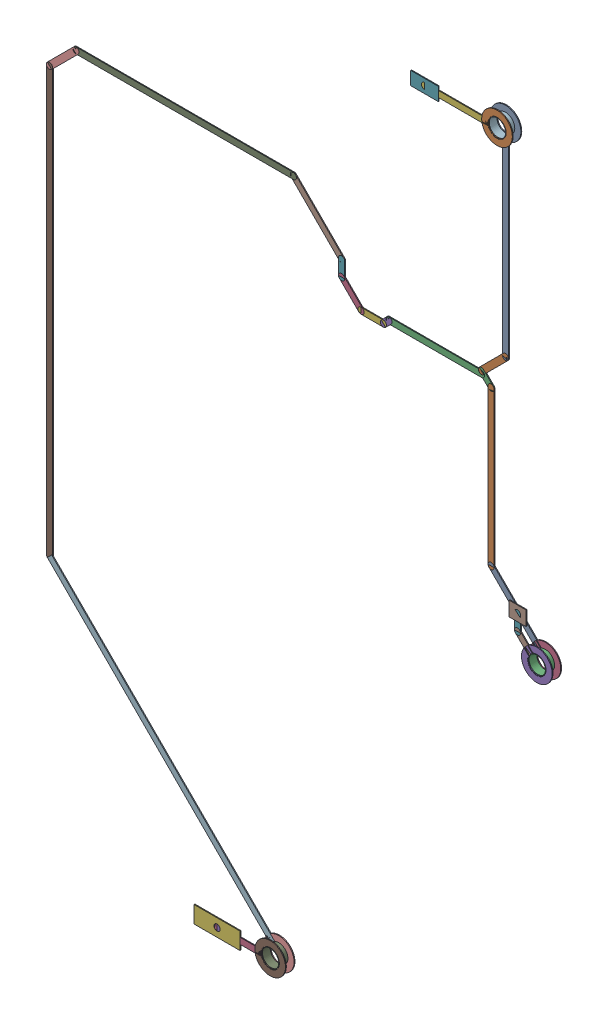
SolidWorks assembly SCL, configuration Predeterminado. Lengths in mm.
Overall size (21.31 35.77 0.39).
90 component instances, 25 part files, 0 mates.
Components (placement in the parent):
- Track (26.1mm,48.6mm)(26.1mm,57mm) on Bottom Layer-1: Track (26.1mm,48.6mm)(26.1mm,57mm) on Bottom Layer [Predeterminado] at origin size (0.25 8.2 0.04)
  - Track (26.1mm,48.6mm)(26.1mm,57mm) on Bottom Layer-1-1: Track (26.1mm,48.6mm)(26.1mm,57mm) on Bottom Layer-1 [Predeterminado] at (-68.317 -44.187 -0.4013) size (0.25 8.2 0.04)
    - Track (26.1mm,48.6mm)(26.1mm,57mm) on Bottom Layer-Part-1-1: Track (26.1mm,48.6mm)(26.1mm,57mm) on Bottom Layer-Part-1 [Predeterminado] at origin size (0.25 8.2 0.04)
- Track (25.1mm,47.6mm)(26.1mm,48.6mm) on Bottom Layer-1: Track (25.1mm,47.6mm)(26.1mm,48.6mm) on Bottom Layer [Predeterminado] at origin size (1.25 1.25 0.04)
  - Track (25.1mm,47.6mm)(26.1mm,48.6mm) on Bottom Layer-1-1: Track (25.1mm,47.6mm)(26.1mm,48.6mm) on Bottom Layer-1 [Predeterminado] at (-68.317 -44.187 -0.4013) size (1.25 1.25 0.04)
    - Track (25.1mm,47.6mm)(26.1mm,48.6mm) on Bottom Layer-Part-1-1: Track (25.1mm,47.6mm)(26.1mm,48.6mm) on Bottom Layer-Part-1 [Predeterminado] at origin size (1.25 1.25 0.04)
- Track (21.267mm,47.493mm)(25.1mm,47.493mm) on Bottom Layer-1: Track (21.267mm,47.493mm)(25.1mm,47.493mm) on Bottom Layer [Predeterminado] at origin size (4.09 0.25 0.04)
  - Track (21.267mm,47.493mm)(25.1mm,47.493mm) on Bottom Layer-1-1: Track (21.267mm,47.493mm)(25.1mm,47.493mm) on Bottom Layer-1 [Predeterminado] at (-68.317 -44.187 -0.4013) size (4.09 0.25 0.04)
    - Track (21.267mm,47.493mm)(25.1mm,47.493mm) on Bottom Layer-Part-1-1: Track (21.267mm,47.493mm)(25.1mm,47.493mm) on Bottom Layer-Part-1 [Predeterminado] at origin size (4.09 0.25 0.04)
- Track (19.304mm,48.07mm)(20.109mm,47.265mm) on Bottom Layer-1: Track (19.304mm,48.07mm)(20.109mm,47.265mm) on Bottom Layer [Predeterminado] at origin size (1.06 1.06 0.04)
  - Track (19.304mm,48.07mm)(20.109mm,47.265mm) on Bottom Layer-1-1: Track (19.304mm,48.07mm)(20.109mm,47.265mm) on Bottom Layer-1 [Predeterminado] at (-68.317 -44.187 -0.4013) size (1.06 1.06 0.04)
    - Track (19.304mm,48.07mm)(20.109mm,47.265mm) on Bottom Layer-Part-1-1: Track (19.304mm,48.07mm)(20.109mm,47.265mm) on Bottom Layer-Part-1 [Predeterminado] at origin size (1.06 1.06 0.04)
- Track (21.039mm,47.265mm)(21.267mm,47.493mm) on Bottom Layer-1: Track (21.039mm,47.265mm)(21.267mm,47.493mm) on Bottom Layer [Predeterminado] at origin size (0.48 0.48 0.04)
  - Track (21.039mm,47.265mm)(21.267mm,47.493mm) on Bottom Layer-1-1: Track (21.039mm,47.265mm)(21.267mm,47.493mm) on Bottom Layer-1 [Predeterminado] at (-68.317 -44.187 -0.4013) size (0.48 0.48 0.04)
    - Track (21.039mm,47.265mm)(21.267mm,47.493mm) on Bottom Layer-Part-1-1: Track (21.039mm,47.265mm)(21.267mm,47.493mm) on Bottom Layer-Part-1 [Predeterminado] at origin size (0.48 0.48 0.04)
- Track (20.109mm,47.265mm)(21.039mm,47.265mm) on Bottom Layer-1: Track (20.109mm,47.265mm)(21.039mm,47.265mm) on Bottom Layer [Predeterminado] at origin size (1.18 0.25 0.04)
  - Track (20.109mm,47.265mm)(21.039mm,47.265mm) on Bottom Layer-1-1: Track (20.109mm,47.265mm)(21.039mm,47.265mm) on Bottom Layer-1 [Predeterminado] at (-68.317 -44.187 -0.4013) size (1.18 0.25 0.04)
    - Track (20.109mm,47.265mm)(21.039mm,47.265mm) on Bottom Layer-Part-1-1: Track (20.109mm,47.265mm)(21.039mm,47.265mm) on Bottom Layer-Part-1 [Predeterminado] at origin size (1.18 0.25 0.04)
- Track (19.304mm,48.07mm)(19.304mm,48.704mm) on Bottom Layer-1: Track (19.304mm,48.07mm)(19.304mm,48.704mm) on Bottom Layer [Predeterminado] at origin size (0.25 0.89 0.04)
  - Track (19.304mm,48.07mm)(19.304mm,48.704mm) on Bottom Layer-1-1: Track (19.304mm,48.07mm)(19.304mm,48.704mm) on Bottom Layer-1 [Predeterminado] at (-68.317 -44.187 -0.4013) size (0.25 0.89 0.04)
    - Track (19.304mm,48.07mm)(19.304mm,48.704mm) on Bottom Layer-Part-1-1: Track (19.304mm,48.07mm)(19.304mm,48.704mm) on Bottom Layer-Part-1 [Predeterminado] at origin size (0.25 0.89 0.04)
- Track (17.308mm,50.7mm)(19.304mm,48.704mm) on Bottom Layer-1: Track (17.308mm,50.7mm)(19.304mm,48.704mm) on Bottom Layer [Predeterminado] at origin size (2.25 2.25 0.04)
  - Track (17.308mm,50.7mm)(19.304mm,48.704mm) on Bottom Layer-1-1: Track (17.308mm,50.7mm)(19.304mm,48.704mm) on Bottom Layer-1 [Predeterminado] at (-68.317 -44.187 -0.4013) size (2.25 2.25 0.04)
    - Track (17.308mm,50.7mm)(19.304mm,48.704mm) on Bottom Layer-Part-1-1: Track (17.308mm,50.7mm)(19.304mm,48.704mm) on Bottom Layer-Part-1 [Predeterminado] at origin size (2.25 2.25 0.04)
- Track (8.3mm,50.7mm)(17.308mm,50.7mm) on Bottom Layer-1: Track (8.3mm,50.7mm)(17.308mm,50.7mm) on Bottom Layer [Predeterminado] at origin size (9.26 0.25 0.04)
  - Track (8.3mm,50.7mm)(17.308mm,50.7mm) on Bottom Layer-1-1: Track (8.3mm,50.7mm)(17.308mm,50.7mm) on Bottom Layer-1 [Predeterminado] at (-68.317 -44.187 -0.4013) size (9.26 0.25 0.04)
    - Track (8.3mm,50.7mm)(17.308mm,50.7mm) on Bottom Layer-Part-1-1: Track (8.3mm,50.7mm)(17.308mm,50.7mm) on Bottom Layer-Part-1 [Predeterminado] at origin size (9.26 0.25 0.04)
- Track (7.2mm,49.6mm)(8.3mm,50.7mm) on Bottom Layer-1: Track (7.2mm,49.6mm)(8.3mm,50.7mm) on Bottom Layer [Predeterminado] at origin size (1.35 1.35 0.04)
  - Track (7.2mm,49.6mm)(8.3mm,50.7mm) on Bottom Layer-1-1: Track (7.2mm,49.6mm)(8.3mm,50.7mm) on Bottom Layer-1 [Predeterminado] at (-68.317 -44.187 -0.4013) size (1.35 1.35 0.04)
    - Track (7.2mm,49.6mm)(8.3mm,50.7mm) on Bottom Layer-Part-1-1: Track (7.2mm,49.6mm)(8.3mm,50.7mm) on Bottom Layer-Part-1 [Predeterminado] at origin size (1.35 1.35 0.04)
- Track (7.2mm,32mm)(7.2mm,49.6mm) on Bottom Layer-1: Track (7.2mm,32mm)(7.2mm,49.6mm) on Bottom Layer [Predeterminado] at origin size (0.25 17.85 0.04)
  - Track (7.2mm,32mm)(7.2mm,49.6mm) on Bottom Layer-1-1: Track (7.2mm,32mm)(7.2mm,49.6mm) on Bottom Layer-1 [Predeterminado] at (-68.317 -44.187 -0.4013) size (0.25 17.85 0.04)
    - Track (7.2mm,32mm)(7.2mm,49.6mm) on Bottom Layer-Part-1-1: Track (7.2mm,32mm)(7.2mm,49.6mm) on Bottom Layer-Part-1 [Predeterminado] at origin size (0.25 17.85 0.04)
- Track (7.2mm,32mm)(16.7mm,22.5mm) on Bottom Layer-1: Track (7.2mm,32mm)(16.7mm,22.5mm) on Bottom Layer [Predeterminado] at origin size (9.48 9.48 0.04)
  - Track (7.2mm,32mm)(16.7mm,22.5mm) on Bottom Layer-1-1: Track (7.2mm,32mm)(16.7mm,22.5mm) on Bottom Layer-1 [Predeterminado] at (-68.317 -44.187 -0.4013) size (9.48 9.48 0.04)
    - Track (7.2mm,32mm)(16.7mm,22.5mm) on Bottom Layer-Part-1-1: Track (7.2mm,32mm)(16.7mm,22.5mm) on Bottom Layer-Part-1 [Predeterminado] at origin size (9.48 9.48 0.04)
- Track (25.5mm,40.8mm)(27.75mm,38.55mm) on Bottom Layer-1: Track (25.5mm,40.8mm)(27.75mm,38.55mm) on Bottom Layer [Predeterminado] at origin size (2.23 2.23 0.04)
  - Track (25.5mm,40.8mm)(27.75mm,38.55mm) on Bottom Layer-1-1: Track (25.5mm,40.8mm)(27.75mm,38.55mm) on Bottom Layer-1 [Predeterminado] at (-68.317 -44.187 -0.4013) size (2.23 2.23 0.04)
    - Track (25.5mm,40.8mm)(27.75mm,38.55mm) on Bottom Layer-Part-1-1: Track (25.5mm,40.8mm)(27.75mm,38.55mm) on Bottom Layer-Part-1 [Predeterminado] at origin size (2.23 2.23 0.04)
- Track (25.5mm,40.8mm)(25.5mm,47.2mm) on Bottom Layer-1: Track (25.5mm,40.8mm)(25.5mm,47.2mm) on Bottom Layer [Predeterminado] at origin size (0.25 6.65 0.04)
  - Track (25.5mm,40.8mm)(25.5mm,47.2mm) on Bottom Layer-1-1: Track (25.5mm,40.8mm)(25.5mm,47.2mm) on Bottom Layer-1 [Predeterminado] at (-68.317 -44.187 -0.4013) size (0.25 6.65 0.04)
    - Track (25.5mm,40.8mm)(25.5mm,47.2mm) on Bottom Layer-Part-1-1: Track (25.5mm,40.8mm)(25.5mm,47.2mm) on Bottom Layer-Part-1 [Predeterminado] at origin size (0.25 6.65 0.04)
- Track (25.1mm,47.6mm)(25.5mm,47.2mm) on Bottom Layer-1: Track (25.1mm,47.6mm)(25.5mm,47.2mm) on Bottom Layer [Predeterminado] at origin size (0.65 0.65 0.04)
  - Track (25.1mm,47.6mm)(25.5mm,47.2mm) on Bottom Layer-1-1: Track (25.1mm,47.6mm)(25.5mm,47.2mm) on Bottom Layer-1 [Predeterminado] at (-68.317 -44.187 -0.4013) size (0.65 0.65 0.04)
    - Track (25.1mm,47.6mm)(25.5mm,47.2mm) on Bottom Layer-Part-1-1: Track (25.1mm,47.6mm)(25.5mm,47.2mm) on Bottom Layer-Part-1 [Predeterminado] at origin size (0.65 0.65 0.04)
- Track (14.5mm,22.5mm)(16.7mm,22.5mm) on Top Layer-1: Track (14.5mm,22.5mm)(16.7mm,22.5mm) on Top Layer [Predeterminado] at origin size (1.99 0.25 0.04)
  - Track (14.5mm,22.5mm)(16.7mm,22.5mm) on Top Layer-1-1: Track (14.5mm,22.5mm)(16.7mm,22.5mm) on Top Layer-1 [Predeterminado] at (-68.317 -44.187 -0.0457) size (1.99 0.25 0.04)
    - Track (14.5mm,22.5mm)(16.7mm,22.5mm) on Top Layer-Part-1-1: Track (14.5mm,22.5mm)(16.7mm,22.5mm) on Top Layer-Part-1 [Predeterminado] at origin size (1.99 0.25 0.04)
- Track (14.5mm,22.5mm)(14.5mm,22.5mm) on Top Layer-1: Track (14.5mm,22.5mm)(14.5mm,22.5mm) on Top Layer [Predeterminado] at origin size (0.25 0.25 0.04)
  - Track (14.5mm,22.5mm)(14.5mm,22.5mm) on Top Layer-1-1: Track (14.5mm,22.5mm)(14.5mm,22.5mm) on Top Layer-1 [Predeterminado] at (-68.317 -44.187 -0.0457) size (0.25 0.25 0.04)
    - Track (14.5mm,22.5mm)(14.5mm,22.5mm) on Top Layer-Part-1-1: Track (14.5mm,22.5mm)(14.5mm,22.5mm) on Top Layer-Part-1 [Predeterminado] at origin size (0.25 0.25 0.04)
- Track (23.098mm,57mm)(26.1mm,57mm) on Top Layer-1: Track (23.098mm,57mm)(26.1mm,57mm) on Top Layer [Predeterminado] at origin size (2.8 0.25 0.04)
  - Track (23.098mm,57mm)(26.1mm,57mm) on Top Layer-1-1: Track (23.098mm,57mm)(26.1mm,57mm) on Top Layer-1 [Predeterminado] at (-68.317 -44.187 -0.0457) size (2.8 0.25 0.04)
    - Track (23.098mm,57mm)(26.1mm,57mm) on Top Layer-Part-1-1: Track (23.098mm,57mm)(26.1mm,57mm) on Top Layer-Part-1 [Predeterminado] at origin size (2.8 0.25 0.04)
- Track (26.95mm,39.35mm)(26.95mm,40mm) on Top Layer-1: Track (26.95mm,39.35mm)(26.95mm,40mm) on Top Layer [Predeterminado] at origin size (0.25 0.9 0.04)
  - Track (26.95mm,39.35mm)(26.95mm,40mm) on Top Layer-1-1: Track (26.95mm,39.35mm)(26.95mm,40mm) on Top Layer-1 [Predeterminado] at (-68.317 -44.187 -0.0457) size (0.25 0.9 0.04)
    - Track (26.95mm,39.35mm)(26.95mm,40mm) on Top Layer-Part-1-1: Track (26.95mm,39.35mm)(26.95mm,40mm) on Top Layer-Part-1 [Predeterminado] at origin size (0.25 0.9 0.04)
- Track (26.95mm,39.35mm)(27.75mm,38.55mm) on Top Layer-1: Track (26.95mm,39.35mm)(27.75mm,38.55mm) on Top Layer [Predeterminado] at origin size (0.78 0.78 0.04)
  - Track (26.95mm,39.35mm)(27.75mm,38.55mm) on Top Layer-1-1: Track (26.95mm,39.35mm)(27.75mm,38.55mm) on Top Layer-1 [Predeterminado] at (-68.317 -44.187 -0.0457) size (0.78 0.78 0.04)
    - Track (26.95mm,39.35mm)(27.75mm,38.55mm) on Top Layer-Part-1-1: Track (26.95mm,39.35mm)(27.75mm,38.55mm) on Top Layer-Part-1 [Predeterminado] at origin size (0.78 0.78 0.04)
- Via (16.7mm,22.5mm) from Top Layer to Bottom Layer-1: Via (16.7mm,22.5mm) from Top Layer to Bottom Layer [Predeterminado] at origin size (1.27 1.27 0.39)
  - Via Hole-1: Via Hole [Predeterminado] at (16.7 22.5 -0.4013) size (0.76 0.76 0.39)
    - Via Hole-Part-1-1: Via Hole-Part-1 [Predeterminado] at origin size (0.76 0.76 0.39)
  - Via Top Layer-1: Via Top Layer [Predeterminado] at (16.7 22.5 -0.4013) size (1.27 1.27 0.04)
    - Via Top Layer-Part-1-1: Via Top Layer-Part-1 [Predeterminado] at origin size (1.27 1.27 0.04)
  - Via Top Layer-2: Via Top Layer [Predeterminado] at (16.7 22.5 -0.0457) size (1.27 1.27 0.04)
    - Via Top Layer-Part-1-1: Via Top Layer-Part-1 [Predeterminado] at origin size (1.27 1.27 0.04)
- Via (26.1mm,57mm) from Top Layer to Bottom Layer-1: Via (26.1mm,57mm) from Top Layer to Bottom Layer [Predeterminado] at origin size (1.27 1.27 0.39)
  - Via Hole-1: Via Hole [Predeterminado] at (26.0999 57.0001 -0.4013) size (0.76 0.76 0.39)
    - Via Hole-Part-1-1: Via Hole-Part-1 [Predeterminado] at origin size (0.76 0.76 0.39)
  - Via Top Layer-1: Via Top Layer [Predeterminado] at (26.0999 57.0001 -0.4013) size (1.27 1.27 0.04)
    - Via Top Layer-Part-1-1: Via Top Layer-Part-1 [Predeterminado] at origin size (1.27 1.27 0.04)
  - Via Top Layer-2: Via Top Layer [Predeterminado] at (26.0999 57.0001 -0.0457) size (1.27 1.27 0.04)
    - Via Top Layer-Part-1-1: Via Top Layer-Part-1 [Predeterminado] at origin size (1.27 1.27 0.04)
- Via (27.75mm,38.55mm) from Top Layer to Bottom Layer-1: Via (27.75mm,38.55mm) from Top Layer to Bottom Layer [Predeterminado] at origin size (1.27 1.27 0.39)
  - Via Hole-1: Via Hole [Predeterminado] at (27.75 38.55 -0.4013) size (0.76 0.76 0.39)
    - Via Hole-Part-1-1: Via Hole-Part-1 [Predeterminado] at origin size (0.76 0.76 0.39)
  - Via Top Layer-1: Via Top Layer [Predeterminado] at (27.75 38.55 -0.4013) size (1.27 1.27 0.04)
    - Via Top Layer-Part-1-1: Via Top Layer-Part-1 [Predeterminado] at origin size (1.27 1.27 0.04)
  - Via Top Layer-2: Via Top Layer [Predeterminado] at (27.75 38.55 -0.0457) size (1.27 1.27 0.04)
    - Via Top Layer-Part-1-1: Via Top Layer-Part-1 [Predeterminado] at origin size (1.27 1.27 0.04)
- Pad RAK4600-5(14.5mm,22.5mm) on Top Layer-1: Pad RAK4600-5(14.5mm,22.5mm) on Top Layer [Predeterminado] at origin size (1.9 0.7 0.04)
  - Pad RAK4600-5(14.5mm,22.5mm) on Top Layer-1-1: Pad RAK4600-5(14.5mm,22.5mm) on Top Layer-1 [Predeterminado] at (-68.317 -44.187 -0.0457) size (1.9 0.7 0.04)
    - Pad RAK4600-5(14.5mm,22.5mm) on Top Layer-Part-1-1: Pad RAK4600-5(14.5mm,22.5mm) on Top Layer-Part-1 [Predeterminado] at origin size (1.9 0.7 0.04)
- Pad ADXL345-14(23.098mm,57mm) on Top Layer-1: Pad ADXL345-14(23.098mm,57mm) on Top Layer [Predeterminado] at origin size (1.14 0.55 0.04)
  - Pad ADXL345-14(23.098mm,57mm) on Top Layer-1-1: Pad ADXL345-14(23.098mm,57mm) on Top Layer-1 [Predeterminado] at (-68.317 -44.187 -0.0457) size (1.14 0.55 0.04)
    - Pad ADXL345-14(23.098mm,57mm) on Top Layer-Part-1-1: Pad ADXL345-14(23.098mm,57mm) on Top Layer-Part-1 [Predeterminado] at origin size (1.14 0.55 0.04)
- Pad R1-1(26.95mm,40mm) on Top Layer-1: Pad R1-1(26.95mm,40mm) on Top Layer [Predeterminado] at origin size (0.7 0.6 0.04)
  - Pad R1-1(26.95mm,40mm) on Top Layer-1-1: Pad R1-1(26.95mm,40mm) on Top Layer-1 [Predeterminado] at (-68.317 -44.187 -0.0457) size (0.7 0.6 0.04)
    - Pad R1-1(26.95mm,40mm) on Top Layer-Part-1-1: Pad R1-1(26.95mm,40mm) on Top Layer-Part-1 [Predeterminado] at origin size (0.7 0.6 0.04)
